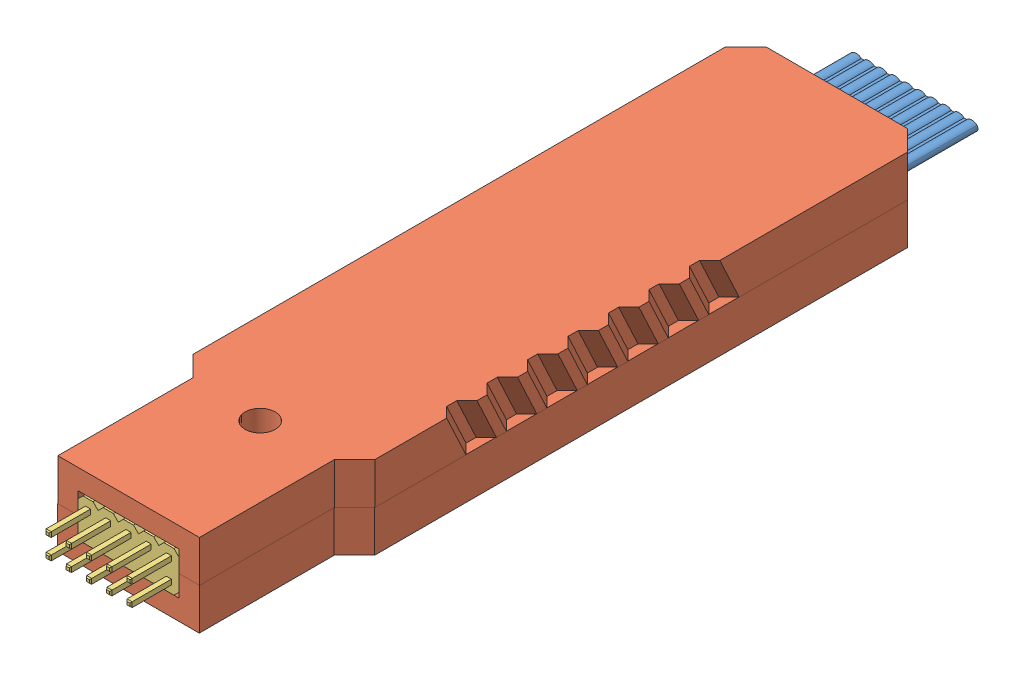
SolidWorks assembly DeviceConnectorRibbon, configuration Default. Lengths in mm.
Overall size (18.02 8.2 81.66).
5 component instances, 4 part files, 22 mates.
Components (placement in the parent):
- RibbonCable^DeviceConnectorRibbon-1: RibbonCable^DeviceConnectorRibbon [Default] at (0 0 -17.6612) x (0 0 -1) z (1 0 0) size (65 4.27 12.76) (virtual)
- EnclosureBody^DeviceConnectorRibbon-1: EnclosureBody^DeviceConnectorRibbon [Default] at (0 -4 -35) x (0 0 -1) z (1 0 0) size (70 5.38 18) (virtual)
- Lid^DeviceConnector-1: Lid^DeviceConnector [Default] at (0 0.1 -27.487) x (0 0 -1) z (1 0 0) (suppressed, hidden, virtual)
- PLD2-NN (DS-1025-05 - 2xNN) 2mm^DeviceConnectorRibbon-1: PLD2-NN (DS-1025-05 - 2xNN) 2mm^DeviceConnectorRibbon [DS1021-2x5] at (4 0 0) x (-1 0 0) z (0 0 -1) size (10 4 8.8) (virtual)
- EnclosureBody^DeviceConnectorRibbon-1: EnclosureBody^DeviceConnectorRibbon [Default] at (0.0194 4.2 -35) x (0 0 -1) z (-1 0 0) size (70 5.38 18) (virtual)
Mates (geometry in assembly coordinates):
- Coincident4: coincident aligned: plane of EnclosureBody^cable-1 through (0 -2 0.1) normal (0 0 1); plane of Lid^cable-1 through (0 2.1 0.013) normal (0 0 1)
- Coincident5: coincident anti-aligned: plane of EnclosureBody^cable-1 through (0 0.1 -34.9) normal (0 1 0); plane of Lid^cable-1 through (0 0.1 -27.487) normal (0 -1 0)
- Concentric1: concentric anti-aligned: cylinder of Self Tapping Cross recessed Screw 4Plastic^cable-1 through (-14 -8 -8.287) axis (0 -1 0) radius 0.78; cylinder of Lid^cable-1 through (-14 2.1 -8.287) axis (0 1 0) radius 1.5
- Coincident7: coincident aligned: cone of Self Tapping Cross recessed Screw 4Plastic^cable-1 through (-14 0.48 -8.287) axis (0 -1 0); cone of Lid^cable-1 through (-14 2.1 -8.287) axis (0 -1 0)
- Concentric2: concentric anti-aligned: cylinder of Self Tapping Cross recessed Screw 4Plastic^cable-2 through (14 -8 -8.287) axis (0 -1 0) radius 0.78; cylinder of Lid^cable-1 through (14 2.1 -8.287) axis (0 1 0) radius 1.5
- Coincident8: coincident aligned: cone of Self Tapping Cross recessed Screw 4Plastic^cable-2 through (14 0.48 -8.287) axis (0 -1 0); cone of Lid^cable-1 through (14 2.1 -8.287) axis (0 -1 0)
- Coincident10: coincident aligned: plane of board^cable-1 through (-0.9944 1 -14.4999) normal (0 1 0); plane of RibbonCable^DeviceConnector-1 through (0 0 -17.6612) normal (0 1 0)
- Coincident11: coincident anti-aligned: plane of board^cable-1 through (-0.9944 1 -14.4999) normal (0 1 0); plane of PBD-20-1 through (10.4356 1 0.5001) normal (0 -1 0)
- Coincident12: coincident anti-aligned: plane of board^cable-1 through (-13.8944 1.75 0.5001) normal (0 0 1); plane of PBD-20-1 through (9.1656 -1.54 0.5001) normal (0 0 -1)
- Coincident13: coincident anti-aligned: plane of EnclosureBody^cable-1 through (0 -4 -34.9) normal (1 0 0); plane of PBD-20-1 through (-0.9944 -0.27 0.5001) normal (-1 0 0)
- Coincident14: coincident anti-aligned: plane of RibbonCable^DeviceConnector-1 through (0 0 -17.6612) normal (1 0 0); plane of PBD-20-1 through (-0.9944 -0.27 0.5001) normal (-1 0 0)
- Coincident15: coincident anti-aligned: plane of EnclosureBody^cable-1 through (0 -0.95 -34.9) normal (0 1 0); plane of PBD-20-1 through (10.4356 1 0.5001) normal (0 -1 0)
- Coincident16: coincident aligned: plane of board^cable-1 through (-0.9944 1 -14.4999) normal (-1 0 0); plane of PBD-20-1 through (-0.9944 -0.27 0.5001) normal (-1 0 0)
- Concentric3: concentric anti-aligned: cylinder of board^cable-1 through (13.0056 0.25 -6.9999) axis (0 1 0) radius 3.4; cylinder of EnclosureBody^cable-1 through (5.0056 3.65 -8.287) axis (0 -1 0) radius 3.1
- Coincident17: coincident aligned: plane of EnclosureBody^cable-1 through (0 -4 -34.9) normal (1 0 0); plane of Lid^cable-1 through (0 0.1 -27.487) normal (1 0 0)
- Coincident18: coincident anti-aligned: plane of board^cable-1 through (-13.8944 1.75 0.5001) normal (0 0 1); plane of PLD2-NN (DS-1025-05 - 2xNN) 2mm^DeviceConnector-1 through (10 1.3335 -1.6) normal (0 0 -1)
- Coincident23: coincident anti-aligned: plane of EnclosureBody^cable-1 through (-5 0.1 -34.9) normal (1 0 0); plane of PLD2-NN (DS-1025-05 - 2xNN) 2mm^DeviceConnector-1 through (-5 2 -2) normal (-1 0 0)
- Coincident24: coincident anti-aligned: plane of EnclosureBody^cable-1 through (0 0.1 -34.9) normal (0 1 0); plane of EnclosureBody^DeviceConnector-1 through (0.0194 0.1 -35) normal (0 -1 0)
- Coincident25: coincident aligned: plane of RibbonCable^DeviceConnector-1 through (0 0 -17.6612) normal (1 0 0); plane of PLD2-NN (DS-1025-05 - 2xNN) 2mm^DeviceConnector-1 through (0 0 0) normal (1 0 0)
- Coincident26: coincident anti-aligned: plane of PLD2-NN (DS-1025-05 - 2xNN) 2mm^DeviceConnector-1 through (4 0 -2) normal (0 0 -1); plane of EnclosureBody^DeviceConnector-1 through (3.5194 0.2 -2) normal (0 0 1)
- Coincident28: coincident aligned: plane of RibbonCable^DeviceConnector-1 through (0 0 -17.6612) normal (0 1 0); plane of PLD2-NN (DS-1025-05 - 2xNN) 2mm^DeviceConnector-1 through (4 0 0) normal (0 1 0)
- Coincident29: coincident aligned: plane of EnclosureBody^cable-1 through (0 -2 0) normal (0 0 1); plane of EnclosureBody^DeviceConnector-1 through (0.0194 2.2 0) normal (0 0 1)
